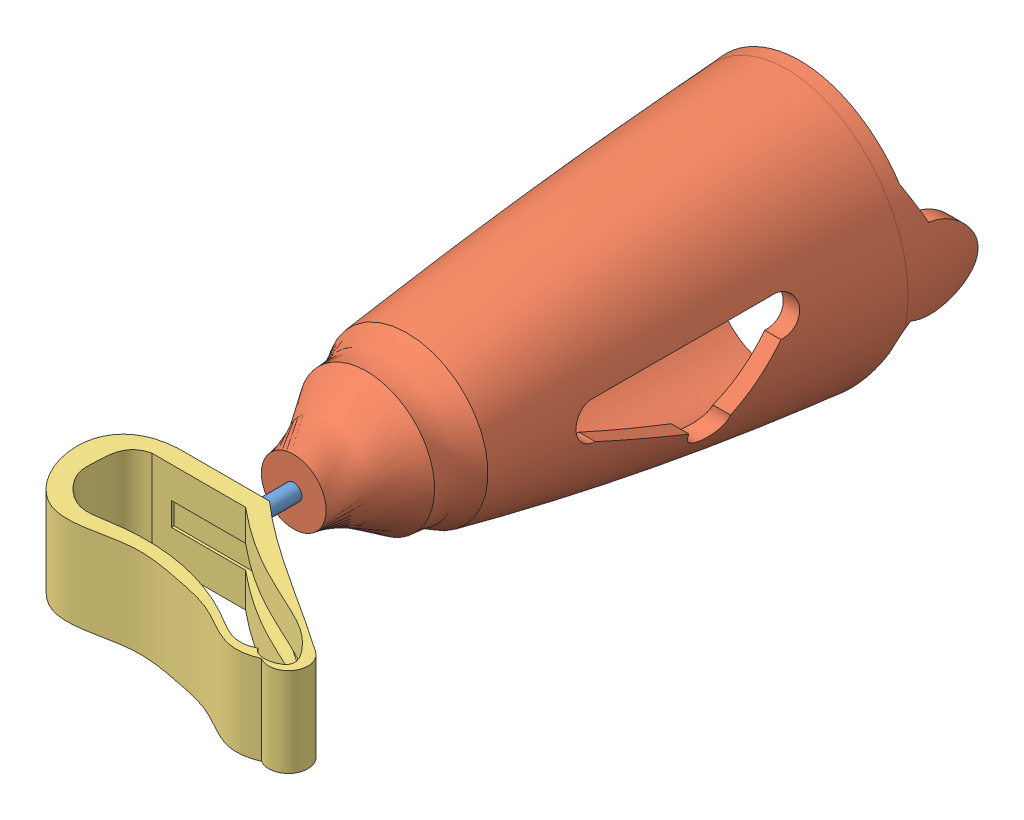
SolidWorks assembly Assem1, configuration Default. Lengths in mm.
Overall size (201.48 167.83 479.38).
4 component instances, 4 part files, 4 mates.
Components (placement in the parent):
- Part1-1: Part1 [Default] at (42.7039 76.2301 113.4031)
- Part3-1: Part3 [Default] at (78.6485 76.2301 13.1234) x (0.976256 -0.21662 0) z (0 0 1) size (10 10 40)
- Part8-2: Part8 [Default] at (78.6485 76.2301 -56.8766) x (1 0 0) z (0 1 0) size (152.53 348.7 167.83)
- Part9-1: Part9 [Default] at (53.6485 48.7301 53.1234) size (189.16 55 91.8)
Mates (geometry in assembly coordinates):
- Coincident18: coincident: plane of assembly; plane of assembly; plane of Part3-1 through (78.6485 76.2301 13.1234) normal (0 0 -1); plane of Part8-2 through (78.6485 76.2301 13.1234) normal (0 0 1)
- Concentric7: concentric: cylinder of assembly; cylinder of assembly; cylinder of Part3-1 through (78.6485 76.2301 53.1234) axis (0 0 -1) radius 5; cylinder of Part8-2 through (78.6485 76.2301 6.1234) axis (0 0 1) radius 5
- Coincident22: coincident: plane of assembly; plane of assembly; plane of Part3-1 through (78.6485 76.2301 53.1234) normal (0 0 1); plane of Part9-1 through (53.6485 103.7301 53.1234) normal (0 0 -1)
- Concentric8: concentric: cylinder of assembly; cylinder of assembly; cylinder of Part3-1 through (78.6485 76.2301 53.1234) axis (0 0 -1) radius 5; cylinder of Part9-1 through (78.6485 76.2301 60.1234) axis (0 0 -1) radius 5
